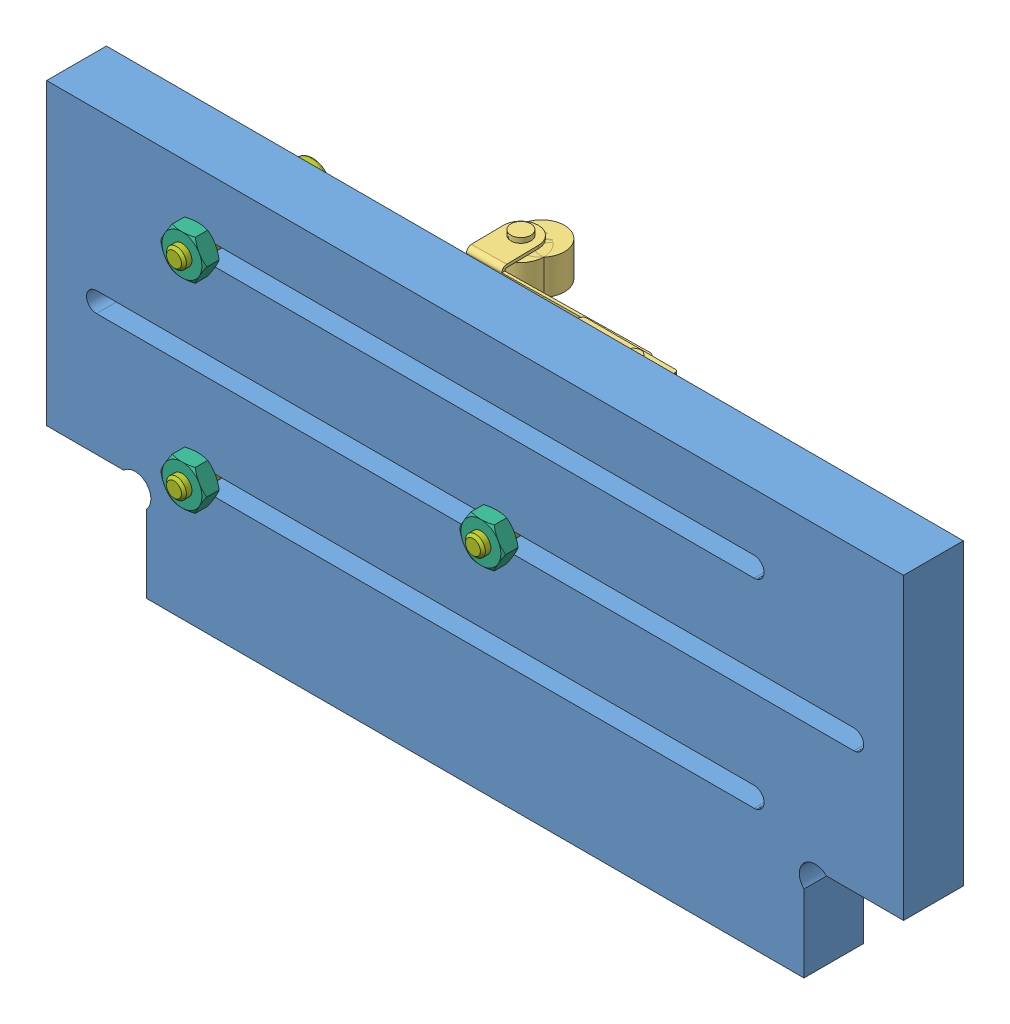
SolidWorks assembly fdc_ferme, configuration Défaut. Lengths in mm.
Overall size (86 40 30.8).
14 component instances, 7 part files, 27 mates.
Components (placement in the parent):
- fdc-platine-1: fdc-platine [Défaut] at (140.8628 -70 0) x (0 0 1) z (0 -1 0) size (6 86 40)
- Grove microswitch v1.0-1: Grove microswitch v1.0 [Défaut] at (-58.8307 23.25 -3.344) x (1 0 0) z (0 1 0) size (41.8 22.4 23.6)
  - PCB grove 20x40-1: PCB grove 20x40 [Défaut] at (-1.988 -1.344 0) size (41.8 1.6 23.6)
  - microswitch 10T85-1: microswitch 10T85 [Défaut] at (9.562 0.256 0) size (22.48 22.4 6.4)
  - Connecteur Grove (coudé CMS)-1: Connecteur Grove (coudé CMS) [Défaut] at (-21.488 0.256 0) x (0 0 -1) z (0 1 0) size (12 10 5)
- entretoise-grove-1: entretoise-grove [Défaut] at (-40.8187 23.25 -2) x (1 0.000242 0) z (0 0 1) size (4 4 2)
- entretoise-grove-2: entretoise-grove [Défaut] at (-70.8187 13.25 -2) size (4 4 2)
- entretoise-grove-3: entretoise-grove [Défaut] at (-70.8187 33.25 -2) size (4 4 2)
- ecrou-h-1: ecrou-h [6007 HU M2] at (-40.8187 23.25 7.6) x (0.866025 -0.5 0) z (-0.5 -0.866025 0) size (4 1.6 4.62)
- ecrou-h-2: ecrou-h [6007 HU M2] at (-70.8187 13.25 7.6) x (0.866025 0.5 0) z (0.5 -0.866025 0) size (4 1.6 4.62)
- ecrou-h-3: ecrou-h [6007 HU M2] at (-70.8187 33.25 7.6) x (-0.866025 0.5 0) z (0.5 0.866025 0) size (4 1.6 4.62)
- vis-chc-1: vis-chc [Vis CHC M2x12] at (-70.8187 13.25 -3.6) x (1 0 0) z (0 1 0) size (3.8 14 3.8)
- vis-chc-2: vis-chc [Vis CHC M2x12] at (-70.8187 33.25 -3.6) x (1 0 0) z (0 1 0) size (3.8 14 3.8)
- vis-chc-3: vis-chc [Vis CHC M2x12] at (-40.8187 23.25 -3.6) x (0.997694 0.067868 0) z (-0.067868 0.997694 0) size (3.8 14 3.8)
Mates (geometry in assembly coordinates):
- Coïncidente1: coincident anti-aligned: plane of cfc-platine-1 through (-8.8686 8.8686 0) normal (0 0 -1)
- Coïncidente2: coincident anti-aligned: plane of cfc-platine-1 through (-10 0 6) normal (0 -1 0)
- Coaxiale1: concentric anti-aligned: cylinder of Grove microswitch v1.0-1/PCB grove 20x40-1 through (-70.8187 33.25 -3.6) axis (0 0 1) radius 1.1; cylinder of entretoise-grove-3 through (-70.8187 33.25 0) axis (0 0 -1) radius 1.2
- Coïncidente4: coincident anti-aligned: plane of Grove microswitch v1.0-1/PCB grove 20x40-1 through (-60.8187 23.25 -2) normal (0 0 1); plane of entretoise-grove-3 through (-70.8187 33.25 -2) normal (0 0 -1)
- Coaxiale2: concentric anti-aligned: cylinder of Grove microswitch v1.0-1/PCB grove 20x40-1 through (-40.8187 23.25 -3.6) axis (0 0 1) radius 1.1; cylinder of entretoise-grove-1 through (-40.8187 23.25 0) axis (0 0 -1) radius 1.2
- Coïncidente5: coincident anti-aligned: plane of Grove microswitch v1.0-1/PCB grove 20x40-1 through (-60.8187 23.25 -2) normal (0 0 1); plane of entretoise-grove-1 through (-40.8187 23.25 -2) normal (0 0 -1)
- Coaxiale3: concentric anti-aligned: cylinder of Grove microswitch v1.0-1/PCB grove 20x40-1 through (-70.8187 13.25 -3.6) axis (0 0 1) radius 1.1; cylinder of entretoise-grove-2 through (-70.8187 13.25 0) axis (0 0 -1) radius 1.2
- Coïncidente6: coincident anti-aligned: plane of Grove microswitch v1.0-1/PCB grove 20x40-1 through (-60.8187 23.25 -2) normal (0 0 1); plane of entretoise-grove-2 through (-70.8187 13.25 -2) normal (0 0 -1)
- Coïncidente7: coincident anti-aligned: plane of cfc-platine-1 through (-8.8686 8.8686 0) normal (0 0 -1); plane of entretoise-grove-1 through (-40.8187 23.25 0) normal (0 0 1)
- Parallèle4: parallel anti-aligned: plane of cfc-platine-1 through (-86 40 6) normal (-1 0 0); plane of Grove microswitch v1.0-1/PCB grove 20x40-1 through (-40.8187 23.25 -3.6) normal (1 0 0)
- Parallèle3: parallel anti-aligned: plane of cfc-platine-1 through (-10 0 6) normal (0 -1 0); plane of Grove microswitch v1.0-1/PCB grove 20x40-1 through (-60.8187 33.25 -3.6) normal (0 1 0)
- Coaxiale4: concentric anti-aligned: cylinder of Grove microswitch v1.0-1/PCB grove 20x40-1 through (-70.8187 13.25 -3.6) axis (0 0 1) radius 1.1; cylinder of vis-chc-1 through (-70.8187 13.25 8.4) axis (0 0 -1) radius 1
- Coaxiale5: concentric anti-aligned: cylinder of Grove microswitch v1.0-1/PCB grove 20x40-1 through (-40.8187 23.25 -3.6) axis (0 0 1) radius 1.1; cylinder of vis-chc-3 through (-40.8187 23.25 8.4) axis (0 0 -1) radius 1
- Coaxiale6: concentric anti-aligned: cylinder of Grove microswitch v1.0-1/PCB grove 20x40-1 through (-70.8187 33.25 -3.6) axis (0 0 1) radius 1.1; cylinder of vis-chc-2 through (-70.8187 33.25 8.4) axis (0 0 -1) radius 1
- Coïncidente11: coincident anti-aligned: plane of Grove microswitch v1.0-1/PCB grove 20x40-1 through (-60.8187 23.25 -3.6) normal (0 0 -1); plane of vis-chc-3 through (-40.8187 23.25 -3.6) normal (0 0 1)
- Coïncidente12: coincident anti-aligned: plane of Grove microswitch v1.0-1/PCB grove 20x40-1 through (-60.8187 23.25 -3.6) normal (0 0 -1); plane of vis-chc-2 through (-70.8187 33.25 -3.6) normal (0 0 1)
- Coïncidente13: coincident anti-aligned: plane of Grove microswitch v1.0-1/PCB grove 20x40-1 through (-60.8187 23.25 -3.6) normal (0 0 -1); plane of vis-chc-1 through (-70.8187 13.25 -3.6) normal (0 0 1)
- Coaxiale7: concentric anti-aligned: cylinder of ecrou-h-2 through (-70.8187 13.25 6) axis (0 0 1) radius 0.7835; cylinder of vis-chc-1 through (-70.8187 13.25 8.4) axis (0 0 -1) radius 1
- Coaxiale8: concentric anti-aligned: cylinder of ecrou-h-3 through (-70.8187 33.25 6) axis (0 0 1) radius 0.7835; cylinder of vis-chc-2 through (-70.8187 33.25 8.4) axis (0 0 -1) radius 1
- Coaxiale9: concentric anti-aligned: cylinder of ecrou-h-1 through (-40.8187 23.25 6) axis (0 0 1) radius 0.7835; cylinder of vis-chc-3 through (-40.8187 23.25 8.4) axis (0 0 -1) radius 1
- Coïncidente14: coincident anti-aligned: plane of cfc-platine-1 through (-8.8686 8.8686 6) normal (0 0 1); plane of ecrou-h-2 through (-69.664 15.25 6) normal (0 0 -1)
- Coïncidente15: coincident anti-aligned: plane of cfc-platine-1 through (-8.8686 8.8686 6) normal (0 0 1); plane of ecrou-h-1 through (-38.5093 23.25 6) normal (0 0 -1)
- Coïncidente16: coincident anti-aligned: plane of cfc-platine-1 through (-8.8686 8.8686 6) normal (0 0 1); plane of ecrou-h-3 through (-73.1281 33.25 6) normal (0 0 -1)
- Parallèle5: parallel aligned: plane of cfc-platine-1 through (0 40 6) normal (0 1 0); plane of ecrou-h-2 through (-69.664 15.25 6) normal (0 1 0)
- Parallèle6: parallel aligned: plane of ecrou-h-1 through (-39.664 25.25 6) normal (0 1 0); plane of ecrou-h-2 through (-69.664 15.25 6) normal (0 1 0)
- Parallèle7: parallel aligned: plane of ecrou-h-2 through (-69.664 15.25 6) normal (0 1 0); plane of ecrou-h-3 through (-69.664 35.25 6) normal (0 1 0)
- Tangent1: tangent anti-aligned: plane of cfc-platine-1 through (-5 22.25 6) normal (0 1 0); cylinder of vis-chc-3 through (-40.8187 23.25 8.4) axis (0 0 -1) radius 1
